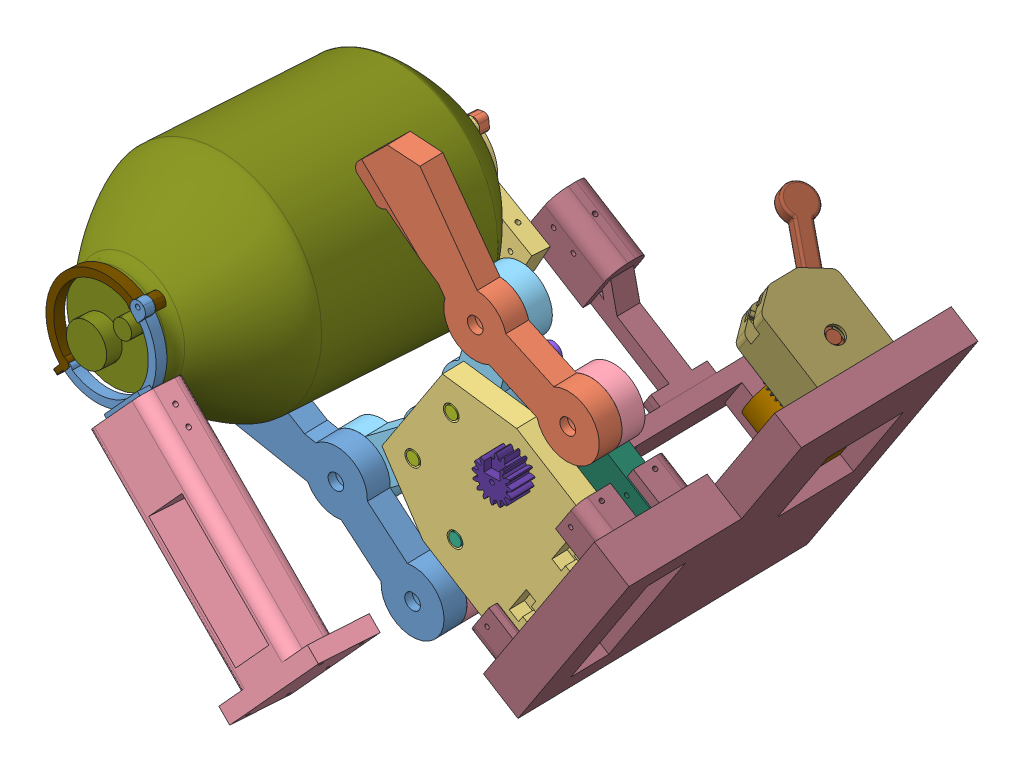
SolidWorks assembly New-model, configuration Default. Lengths in mm.
Overall size (367.09 323.38 379.92).
30 component instances, 22 part files, 52 mates.
Components (placement in the parent):
- Cang-New-1: Cang-New [Default] at (-23.2156 -114.4889 66.5678) x (-0.655477 -0.755178 0.007503) z (-0.016818 0.004664 -0.999848) size (68.97 177.31 15)
- Cang-New-1-1: Cang-New-1 [Default] at (68.9816 22.3597 50.6531) x (0.443475 0.896281 -0.003279) z (0.016818 -0.004664 0.999848) size (68.97 177.31 15)
- Case-New-1: Case-New [Default] at (-21.9426 -99.8772 51.6123) x (0.545967 0.83779 -0.005275) z (0.016818 -0.004664 0.999848) size (110.04 110 14)
- TestTayDonDai-1: TestTayDonDai [Default] at (90.455 -18.5083 35.099) x (0.646413 0.762953 -0.007314) z (0.016818 -0.004664 0.999848) size (88.9 40 15)
- TestTayDonNgan-1: TestTayDonNgan [Default] at (-32.2115 -85.8412 36.8482) x (-0.800288 -0.599521 0.010664) z (0.016818 -0.004664 0.999848) size (100.12 40.15 15)
- TestTayDonDai-2: TestTayDonDai [Default] at (28.8111 -121.9928 35.6532) x (-0.487277 -0.873238 0.004123) z (0.016818 -0.004664 0.999848) size (88.9 40 15)
- TestTayDonNgan-2: TestTayDonNgan [Default] at (59.3269 13.8217 35.7734) x (0.27628 0.961077 -0.000164) z (0.016818 -0.004664 0.999848) size (100.12 40.15 15)
- LongCoil-1: LongCoil [Default] at (66.6427 -29.9569 64.4506) x (-0.762803 0.646437 0.015846) z (-0.016818 0.004664 -0.999848) size (8.4 13.14 55)
- LongCoil-2: LongCoil [Default] at (24.9218 -92.0687 9.8542) x (-0.873085 0.487272 0.016958) z (0.016818 -0.004664 0.999848) size (8.4 13.14 55)
- Coil45mm-1: Coil45mm [Default] at (43.5271 -29.4734 4.8325) x (0.999858 0.000465 -0.016816) z (0.016818 -0.004664 0.999848) size (7.98 7.98 60)
- Coil45mm-2: Coil45mm [Default] at (18.9586 -67.1739 5.0699) x (0.999858 0.000465 -0.016816) z (0.016818 -0.004664 0.999848) size (7.98 7.98 60)
- Gear-iso_Small-Assistant-1: Gear-iso_Small-Assistant [Default] at (36.9087 -26.6582 -2.0441) x (0.809997 -0.586206 -0.016359) z (0.016818 -0.004664 0.999848) size (14 21.69 17)
- Model-1: Model [Default] at (127.8789 66.6924 50.8113) x (0.526512 0.805365 -0.272345) z (0.140898 0.233253 0.962154) size (244.58 190.3 241.17)
  - Assem1^Model-1: Assem1^Model [Default] at (3.4657 -14.9182 -28.9572) x (-1 0 0) z (0 1 0) (virtual)
  - Motor-support-1: Motor-support [Default] at (-64.909 -83.1871 -147.3059) x (0.963622 -0.001135 0.267267) z (-0.005849 0.999662 0.025335) size (88 49 37)
  - rack spur rectangular_am-1: rack spur rectangular_am [Metric - Rack-spur - rectangular 1M 20PA 7FW 5PH 50L---SAll] at (-27.132 -76.2765 -162.5934) x (-0.267205 -0.025976 0.963289) z (-0.963622 0.001135 -0.267267) size (50 6 7)
  - Stick-4: Stick [Default] at (-11.9121 -54.6034 -118.2584) x (0.963622 -0.001135 0.267267) z (-0.231626 0.495386 0.837223) size (22 95.61 20.61)
  - basev2-2: basev2 [Default] at (7.1679 -36.3233 -119.6245) x (-0.267205 -0.025976 0.963289) z (-0.963622 0.001135 -0.267267) size (65 65 30)
  - base-part3-2: base-part3 [Default] at (-81.3746 -93.1499 -152.7114) x (0.963622 -0.001135 0.267267) z (-0.005849 0.999662 0.025335) size (200 190 185.2)
  - rack spur rectangular_am-2: rack spur rectangular_am [Metric - Rack-spur - rectangular 1M 20PA 7FW 5PH 50L---SAll] at (-32.5906 -77.5846 -112.2374) x (0.267205 0.025976 -0.963289) z (0.963622 -0.001135 0.267267) size (50 6 7)
  - Gear-v2-3-1: Gear-v2-3 [Default] at (-41.2409 -59.957 -108.235) x (0.963622 -0.001135 0.267267) z (0.133351 0.868672 -0.477102) size (25 36.95 36.98)
- Case-New - Part 3-1: Case-New - Part 3 [Default] at (53.3482 16.2052 32.8846) x (-0.545967 -0.83779 0.005275) z (-0.016818 0.004664 -0.999848) size (110.04 110 14)
- Gear-iso_Small-Assistant-2: Gear-iso_Small-Assistant [Default] at (9.1295 -65.2038 -1.7567) x (0.292454 0.95628 -0.000458) z (0.016818 -0.004664 0.999848) size (14 21.69 17)
- Ambu_bag-1: Ambu_bag [Default] at (-66.2932 23.3189 171.5942) x (1 0 0) z (0 -0.061049 -0.998135) size (143.89 143.89 232)
- spur gear_iso-1: spur gear_iso [ISO - Spur gear 1.5M 15T 20PA 15FW ---S15A75H50L3.0N] at (77.0621 -39.9074 64.2289) x (0.016818 -0.004664 0.999848) z (-0.999848 0.004586 0.016839) size (15 25.29 25.42)
- Mount-Bong-part2-1: Mount-Bong-part2 [Default] at (-64.8048 22.7482 182.0486) x (-0.628845 -0.77608 0.047467) z (0 0.061049 0.998135) size (86 40.95 10.5)
- Mount-Bong-2: Mount-Bong [Default] at (-66.2932 24.3567 188.5625) x (-0.670092 -0.740893 0.045315) z (0 -0.061049 -0.998135) size (86 77.25 15)
- Mount-Bong 2 -Part2-1: Mount-Bong 2 -Part2 [Default] at (-48.9365 7.4983 -42.8399) x (0.17551 -0.982641 0.060101) z (0 0.061049 0.998135) size (64 29.5 13)
- Mount-Bong 2-1: Mount-Bong 2 [Default] at (-66.2932 10.926 -31.0271) x (-0.466287 -0.882983 0.054006) z (0 -0.061049 -0.998135) size (64 67.41 13)
- Base-Nang-Bong-1: Base-Nang-Bong [Default] at (57.6009 -96.0124 183.2021) x (0 -0.061049 -0.998135) z (0.742278 -0.668842 0.040908) size (40 80 148)
Mates (geometry in assembly coordinates):
- Concentric2: concentric aligned: circle of Case-New-1; circle of TestTayDonDai-2
- Concentric3: concentric aligned: circle of Case-New-1; circle of TestTayDonDai-1
- Concentric4: concentric anti-aligned: circle of Cang-New-1-1; circle of TestTayDonDai-1
- Coincident2: coincident anti-aligned: plane of Cang-New-1-1 through (52.9644 29.3492 50.9551) normal (-0.016818 0.004664 -0.999848); plane of TestTayDonDai-1 through (76.8267 -39.8421 50.231) normal (0.016818 -0.004664 0.999848)
- Concentric5: concentric anti-aligned: circle of Cang-New-1; circle of TestTayDonDai-2
- Coincident3: coincident anti-aligned: plane of Cang-New-1 through (-36.0989 -102.3408 51.8389) normal (-0.016818 0.004664 -0.999848); plane of TestTayDonDai-2 through (38.5862 -98.5223 50.6005) normal (0.016818 -0.004664 0.999848)
- Concentric9: concentric anti-aligned: circle of Cang-New-1-1; circle of TestTayDonNgan-2
- Coincident9: coincident anti-aligned: plane of Cang-New-1-1 through (52.9644 29.3492 50.9551) normal (-0.016818 0.004664 -0.999848); plane of TestTayDonNgan-2 through (52.9644 29.3492 50.9551) normal (0.016818 -0.004664 0.999848)
- Concentric10: concentric aligned: circle of Case-New-1; circle of TestTayDonNgan-2
- Concentric12: concentric anti-aligned: circle of Cang-New-1; circle of TestTayDonNgan-1
- Coincident12: coincident anti-aligned: plane of Cang-New-1 through (-36.0989 -102.3408 51.8389) normal (-0.016818 0.004664 -0.999848); plane of TestTayDonNgan-1 through (-36.0989 -102.3408 51.8389) normal (0.016818 -0.004664 0.999848)
- Concentric13: concentric aligned: circle of Case-New-1; circle of TestTayDonNgan-1
- GearMate1: gear = 8.5 : 8.5 mm: circle of TestTayDonDai-1; circle of TestTayDonDai-2
- Concentric19: concentric anti-aligned: circle of Case-New-1; circle of LongCoil-1
- Coincident21: coincident aligned: plane of Case-New-1 through (-21.7071 -99.9425 65.6102) normal (0.016818 -0.004664 0.999848); plane of LongCoil-1 through (77.0621 -39.9074 64.2289) normal (0.016818 -0.004664 0.999848)
- Parallel1: parallel anti-aligned: plane of TestTayDonDai-2 through (36.5627 -107.7824 35.5891) normal (0.487277 0.873238 -0.004123); plane of LongCoil-2 through (36.6645 -107.739 39.5882) normal (-0.487277 -0.873238 0.004123)
- Concentric20: concentric aligned: circle of Case-New-1; circle of Coil45mm-1
- Coincident44: coincident aligned: plane of Case-New-1 through (-21.7071 -99.9425 65.6102) normal (0.016818 -0.004664 0.999848); plane of Coil45mm-1 through (36.7321 -28.5409 64.9603) normal (0.016818 -0.004664 0.999848)
- Parallel6: parallel anti-aligned: plane of Case-New-1 through (-21.9426 -99.8772 51.6123) normal (-0.016818 0.004664 -0.999848); plane of TestTayDonNgan-2 through (52.9644 29.3492 50.9551) normal (0.016818 -0.004664 0.999848)
- Parallel9: parallel anti-aligned: line of TestTayDonDai-1 through (84.6873 -34.837 35.1199) axis (-0.762803 0.646437 0.015846); line of LongCoil-1 through (80.0477 -31.0079 34.2156) axis (0.762803 -0.646437 -0.015846)
- Concentric23: concentric aligned: circle of Case-New-1; circle of LongCoil-2
- Coincident57: coincident aligned: plane of Case-New-1 through (-21.7071 -99.9425 65.6102) normal (0.016818 -0.004664 0.999848); plane of LongCoil-2 through (38.8217 -98.5876 64.5984) normal (0.016818 -0.004664 0.999848)
- Concentric24: concentric aligned: circle of Case-New-1; circle of Coil45mm-2
- Coincident59: coincident aligned: plane of Case-New-1 through (-21.7071 -99.9425 65.6102) normal (0.016818 -0.004664 0.999848); plane of Coil45mm-2 through (12.1635 -66.2414 65.1976) normal (0.016818 -0.004664 0.999848)
- Parallel11: parallel anti-aligned: plane of Case-New-1 through (-21.9426 -99.8772 51.6123) normal (-0.016818 0.004664 -0.999848); plane of TestTayDonNgan-1 through (-36.0989 -102.3408 51.8389) normal (0.016818 -0.004664 0.999848)
- Concentric25: concentric aligned: circle of Coil45mm-1; circle of Gear-iso_Small-Assistant-1
- Concentric26: concentric anti-aligned: circle of Gear-iso_Small-Assistant-1; circle of Case-New - Part 3-1
- Parallel13: parallel anti-aligned: plane of Case-New-1 through (134.0516 -53.1801 63.2084) normal (0.837638 -0.545973 -0.016636); plane of Model-1/base-part3-2 through (119.7531 -70.9772 -72.6548) normal (-0.837638 0.545973 0.016636)
- Coincident64: coincident anti-aligned: plane of Case-New-1 through (134.0516 -53.1801 63.2084) normal (0.837638 -0.545973 -0.016636); plane of Model-1/base-part3-2 through (119.7531 -70.9772 -72.6548) normal (-0.837638 0.545973 0.016636)
- Coincident65: coincident anti-aligned: plane of Model-1/base-part3-2 through (119.7531 -70.9772 -72.6548) normal (-0.837638 0.545973 0.016636); plane of Case-New - Part 3-1 through (73.2215 -145.1225 17.7957) normal (0.837638 -0.545973 -0.016636)
- Coincident67: coincident anti-aligned: plane of Case-New-1 through (-21.9426 -99.8772 51.6123) normal (-0.016818 0.004664 -0.999848); plane of TestTayDonNgan-1 through (-36.0989 -102.3408 51.8389) normal (0.016818 -0.004664 0.999848)
- Coincident68: coincident anti-aligned: plane of Case-New-1 through (-21.9426 -99.8772 51.6123) normal (-0.016818 0.004664 -0.999848); plane of TestTayDonNgan-2 through (52.9644 29.3492 50.9551) normal (0.016818 -0.004664 0.999848)
- Distance1: distance = 3 mm anti-aligned: plane of Case-New - Part 3-1 through (53.3482 16.2052 32.8846) normal (0.016818 -0.004664 0.999848); plane of TestTayDonDai-1 through (76.5744 -39.7722 35.2333) normal (-0.016818 0.004664 -0.999848)
- Concentric27: concentric aligned: circle of Coil45mm-2; circle of Gear-iso_Small-Assistant-2
- Coincident79: coincident anti-aligned: plane of Coil45mm-1 through (35.723 -28.261 4.9694) normal (-0.016818 0.004664 -0.999848); plane of Gear-iso_Small-Assistant-1 through (37.0265 -26.6909 4.9548) normal (0.016818 -0.004664 0.999848)
- Coincident80: coincident anti-aligned: plane of Coil45mm-2 through (11.1545 -65.9616 5.2068) normal (-0.016818 0.004664 -0.999848); plane of Gear-iso_Small-Assistant-2 through (9.2472 -65.2365 5.2422) normal (0.016818 -0.004664 0.999848)
- Concentric31: concentric aligned: circle of Coil45mm-1; circle of Gear-iso_Small-Assistant-1
- Concentric32: concentric aligned: circle of LongCoil-1; circle of spur gear_iso-1
- Coincident85: coincident anti-aligned: plane of Case-New-1 through (-21.7071 -99.9425 65.6102) normal (0.016818 -0.004664 0.999848); plane of spur gear_iso-1 through (77.0621 -39.9074 64.2289) normal (-0.016818 0.004664 -0.999848)
- Coincident88: coincident anti-aligned: plane of Case-New-1 through (-21.7071 -99.9425 65.6102) normal (0.016818 -0.004664 0.999848); plane of Model-1/base-part3-2 through (105.2875 -60.692 63.6572) normal (-0.016818 0.004664 -0.999848)
- Coincident89: coincident anti-aligned: plane of Model-1/base-part3-2 through (54.9552 -133.7833 -71.8579) normal (0.545967 0.83779 -0.005275); plane of Case-New - Part 3-1 through (17.5064 -108.8073 18.9022) normal (-0.545967 -0.83779 0.005275)
- Concentric35: concentric anti-aligned: circle of Ambu_bag-1; circle of Mount-Bong-2
- Coincident95: coincident aligned: plane of Ambu_bag-1 through (-74.6303 15.7925 189.0863) normal (0 0.061049 0.998135); plane of Mount-Bong-2 through (-66.2932 24.3567 188.5625) normal (0 0.061049 0.998135)
- Coincident97: coincident aligned: cylinder of Mount-Bong-part2-1 through (-40.9019 53.1023 173.3793) axis (0 0.061049 0.998135) radius 1.5; circle of Mount-Bong-2
- Coincident98: coincident anti-aligned: plane of Mount-Bong-part2-1 through (-64.8048 22.9435 185.2426) normal (0 0.061049 0.998135); plane of Mount-Bong-2 through (-66.2932 24.1491 185.1689) normal (0 -0.061049 -0.998135)
- Concentric37: concentric aligned: circle of Ambu_bag-1; circle of Mount-Bong 2-1
- Coincident99: coincident aligned: plane of Ambu_bag-1 through (-66.2932 10.1934 -43.0047) normal (0 -0.061049 -0.998135); plane of Mount-Bong 2-1 through (-66.2932 10.1934 -43.0047) normal (0 -0.061049 -0.998135)
- Coincident101: coincident aligned: plane of Mount-Bong 2 -Part2-1 through (-48.9365 7.4983 -42.8399) normal (0 -0.061049 -0.998135); plane of Mount-Bong 2-1 through (-66.2932 10.1934 -43.0047) normal (0 -0.061049 -0.998135)
- Concentric38: concentric anti-aligned: circle of Mount-Bong 2 -Part2-1; circle of Mount-Bong 2-1
- Coincident103: coincident anti-aligned: plane of Mount-Bong-2 through (-12.6618 -24.3962 184.5313) normal (0.742278 -0.668842 0.040908); plane of Base-Nang-Bong-1 through (-16.6269 -29.1281 179.1113) normal (-0.742278 0.668842 -0.040908)
- Coincident104: coincident anti-aligned: plane of Mount-Bong-2 through (-66.2932 23.9293 181.5756) normal (0 -0.061049 -0.998135); plane of Base-Nang-Bong-1 through (-31.1473 11.7679 182.3194) normal (0 0.061049 0.998135)
- Coincident105: coincident anti-aligned: plane of Mount-Bong-2 through (-77.01 12.0802 182.3003) normal (-0.670092 -0.740893 0.045315); plane of Base-Nang-Bong-1 through (-51.5851 -9.8953 198.973) normal (0.670092 0.740893 -0.045315)
